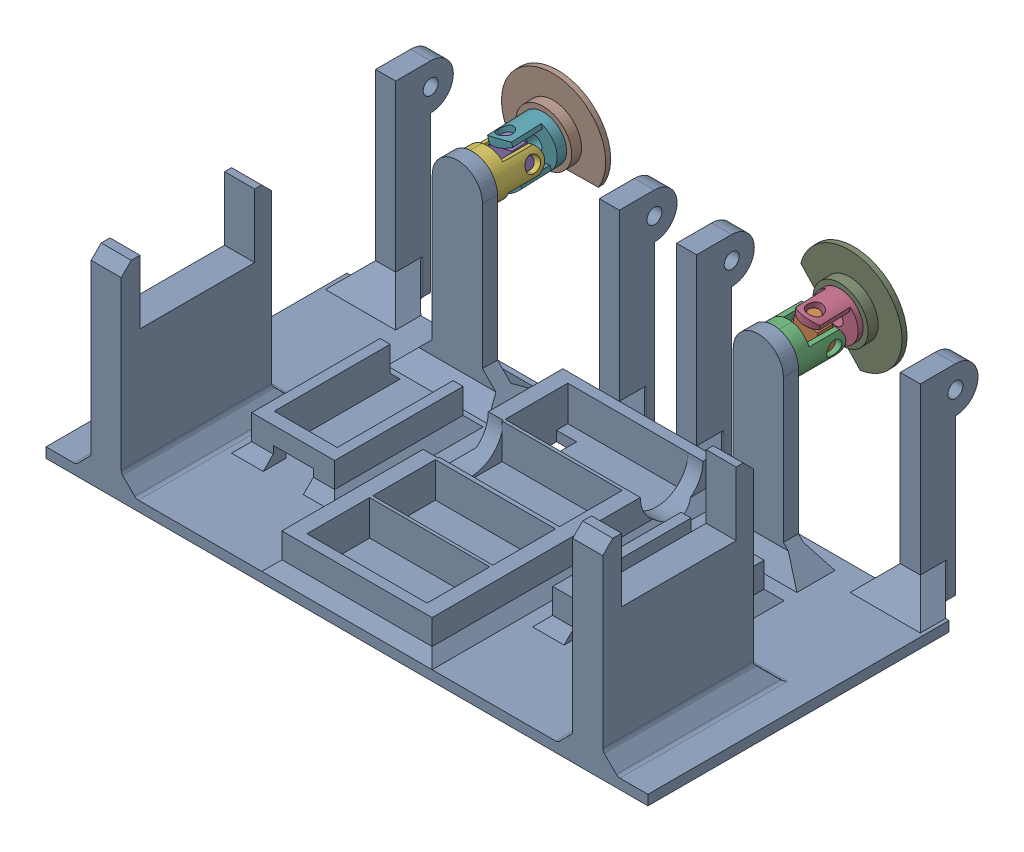
SolidWorks assembly EyeSubSystem, configuration Default. Lengths in mm.
Overall size (120 50.24 72.6).
18 component instances, 7 part files, 0 mates.
Components (placement in the parent):
- EyeAssemblyFinal2-1: EyeAssemblyFinal2 [Default] at (-0.977 -66.1842 232.1524) size (120 50.24 72.6) (flexible)
  - BASE_v3_pasha-4: BASE_v3_pasha [Default] at origin size (120 40.7 71.5)
  - UV_Final-4: UV_Final [Default] at (29.2298 41.5773 -36.6858) x (0.986642 -0.162905 0) z (-0.162819 -0.986118 -0.032589) size (9.05 15.57 9.32)
    - UV cross spider[1].step-1: UV cross spider[1].step [Default] at (1.7499 4.175 5.7377) size (7.2 3 7.2)
    - UV Yoke[1].step-1: UV Yoke[1].step [Default] at (1.7499 11.8709 5.4867) x (1 0 0) z (0 -0.032589 -0.999469) size (9.01 10 9)
    - UV Yoke[1].step-2: UV Yoke[1].step [Default] at (1.7085 -3.5249 5.7377) x (0 0 -1) z (0.999986 -0.005381 0) size (9.01 10 9)
  - UV_Final-5: UV_Final [Default] at (-33.0686 40.802 -36.6858) x (0.972522 0.232812 0) z (0.232689 -0.972005 -0.032589) size (9.05 15.57 9.32)
    - UV cross spider[1].step-1: UV cross spider[1].step [Default] at (1.7499 4.175 5.7377) size (7.2 3 7.2)
    - UV Yoke[1].step-1: UV Yoke[1].step [Default] at (1.7499 11.8709 5.4867) x (1 0 0) z (0 -0.032589 -0.999469) size (9.01 10 9)
    - UV Yoke[1].step-2: UV Yoke[1].step [Default] at (1.7085 -3.5249 5.7377) x (0 0 -1) z (0.999986 -0.005381 0) size (9.01 10 9)
  - eye ball-3: eye ball [Default] at (-30.0207 35.549 -34.3103) x (0.01282 -0.03044 0.999454) z (-0.999706 -0.020948 0.012185) (suppressed, hidden)
  - eye ball-4: eye ball [Default] at (30 35.5231 -33.3996) x (0 -0.033029 0.999454) z (-1 0 0) (suppressed, hidden)
  - UVHOLDERSLDPART-3: UVHOLDERSLDPART [Default] at (-30.1104 35.7621 -41.3065) x (-0.999918 -0.000328 0.012816) z (-0.01282 0.03044 -0.999454) size (20.5 15.75 3)
  - UVHOLDERSLDPART-4: UVHOLDERSLDPART [Default] at (30 35.7543 -40.3958) x (-0.659749 0.751076 0.024821) z (0 0.033029 -0.999454) size (20.5 15.75 3)
- lower_eye_lid-3: lower_eye_lid [Default] at (28.9463 -30.5119 195.4439) x (1 0 0) z (0 -0.275637 0.961262) (suppressed, hidden)
- lower_eye_lid-2: lower_eye_lid [Default] at (-31.099 -30.597 195.3224) x (1 0 0) z (0 -0.267238 0.96363) (suppressed, hidden)
- Upper Eye Lid-1: Upper Eye Lid [Default] at (7.1769 -60.49 168.3753) (suppressed, hidden)
- Upper Eye Lid-2: Upper Eye Lid [Default] at (-52.8237 -60.3757 168.4362) (suppressed, hidden)
